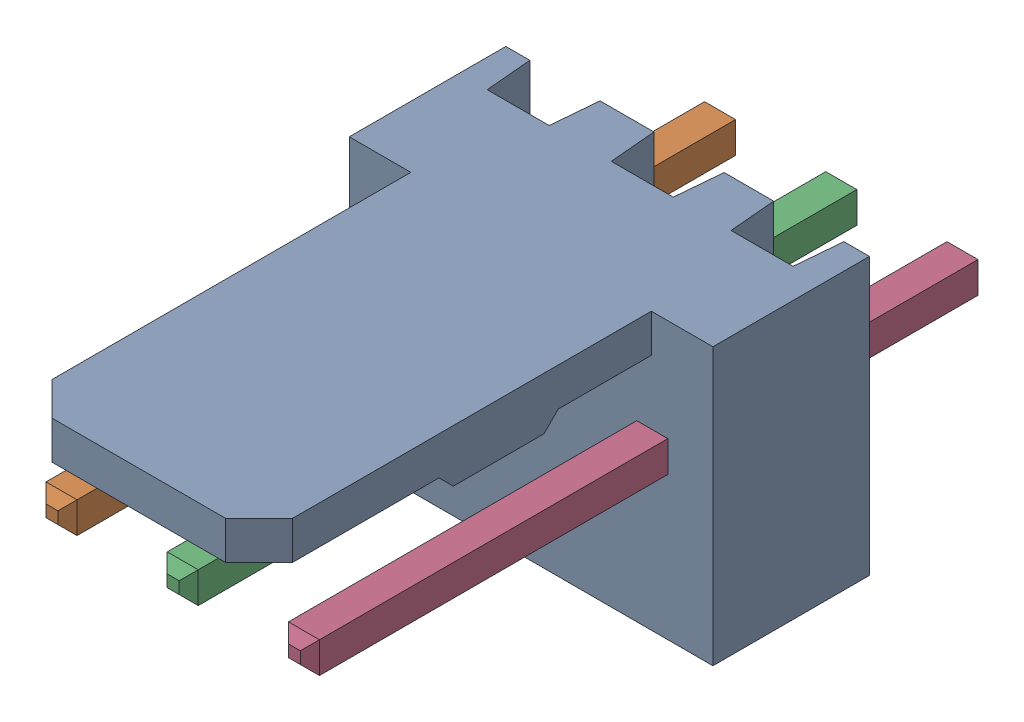
SolidWorks assembly Molex PCB 3 pin v2 v6 (2), configuration Default. Lengths in mm.
Overall size (7.62 5.79 14.92).
4 component instances, 2 part files, 0 mates.
Components (placement in the parent):
- BASE9710016 (1)-1: BASE9710016 (1) [Default] at (2.54 2.895 -8.22) size (7.62 5.79 11.5)
- PINO9710016 (1)-1: PINO9710016 (1) [Default] at (1.27 3.325 -0.72) size (0.65 0.65 14.2)
- PINO9710016 (1)-2: PINO9710016 (1) [Default] at (3.81 3.325 -0.72) size (0.65 0.65 14.2)
- PINO9710016 (1)-3: PINO9710016 (1) [Default] at (6.35 3.325 -0.72) size (0.65 0.65 14.2)
